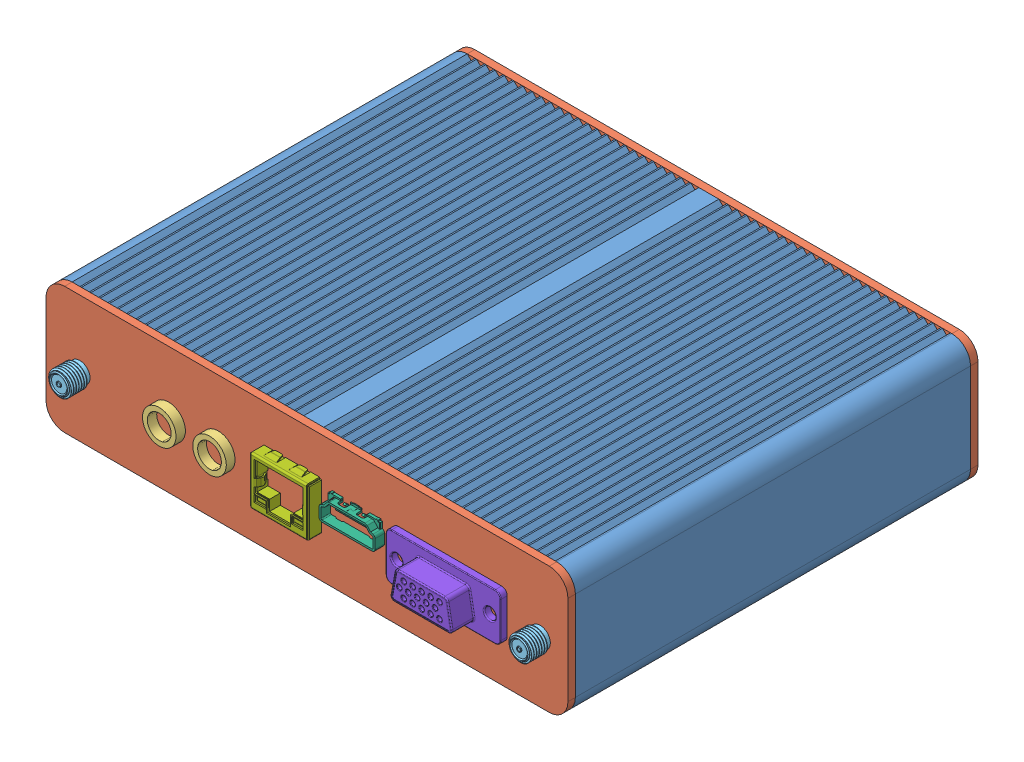
SolidWorks assembly mini computer all, configuration Default. Lengths in mm.
Overall size (140 34 122.68).
23 component instances, 13 part files, 6 mates.
Components (placement in the parent):
- mini computer enclosure body-1: mini computer enclosure body [Default] at (56.7491 81.2226 46.5464) size (140 34 106)
- mini computer back panel-1: mini computer back panel [Default] at (-0.7408 3.8203 51.7955) size (140 34 41.82)
  - mini computer enclosure sides-1: mini computer enclosure sides [Default] at (57.49 77.4023 100.7509) size (140 34 2)
  - 6.35mm jack-1: 6.35mm jack [Default] at (20.382 76.9675 85.7703) size (19 18 36.5)
    - 6.35mm jack-1: 6.35mm jack [Default] at origin size (18 18 36.5)
    - Gnd Plate_6.35mm jack-1: Gnd Plate_6.35mm jack [Default] at (0 0 10) size (17 18 20)
  - 6.35mm jack-2: 6.35mm jack [Default] at (33.7137 76.9223 85.6106) size (19 18 36.5)
    - 6.35mm jack-1: 6.35mm jack [Default] at origin size (18 18 36.5)
    - Gnd Plate_6.35mm jack-1: Gnd Plate_6.35mm jack [Default] at (0 0 10) size (17 18 20)
  - Conector SMA flange 4 furos-1: Conector SMA flange 4 furos [Valor predeterminado] at (-3.4215 76.4747 99.0509) x (1 0 0) z (0 -1 0) size (12.7 27.4 12.7)
  - Conector SMA flange 4 furos-2: Conector SMA flange 4 furos [Valor predeterminado] at (120.0439 76.6956 99.0509) x (1 0 0) z (0 -1 0) size (12.7 27.4 12.7)
  - hdmi female-2: hdmi female [Default] at (70.798 82.8969 105.3066) x (-1 0 0) z (0 0 1) size (15.14 8.38 12.15)
  - RJ45_10P_TJ3009-1: RJ45_10P_TJ3009 [Default] at (53.5571 84.0699 95.5036) x (-1 0 0) z (0 0 1) size (16 15.87 21.5)
  - VGA PORT-1: VGA PORT [По умолчанию] at (95.8113 77.1031 104.5295) x (1 0 0) z (0 0 -1) size (30.8 16.47 22.2)
- mini computer front panel-1: mini computer front panel [Default] at (110.1468 19.0094 232.1895) x (-1 0 0) z (0 0 -1) size (140 34 29)
  - mini computer enclosure sides-1: mini computer enclosure sides [Default] at (53.3977 62.2132 185.6431) size (140 34 2)
  - usb_a-usb_a-lp-c-1: usb_a-usb_a-lp-c [Default] at (55.3305 69.3871 188.406) x (-1 0 0) z (0 0 1) size (12.61 5.8 19.93)
  - usb3x2-1: usb3x2 [Default] at (78.6824 71.2528 188.5685) x (0 -1 0) z (1 0 0) size (19.41 17.47 15.68)
  - usb3x2-2: usb3x2 [Default] at (96.7049 71.3003 188.9318) x (0 -1 0) z (1 0 0) size (19.41 17.47 15.68)
  - Jack 12V DC-1: Jack 12V DC [Default] at (20.8994 57.6127 190.0972) size (9.8 15.1 14.2)
  - Push Button-1: Push Button [Default] at (67.9467 102.816 186.8199) x (1 0 0) z (0 -1 0) size (14.35 29 14.35)
    - Body-1: Body [Default] at (-63.575 0.8231 40.4617) size (14.35 26 14.35)
    - Button-1: Button [Default] at (-63.575 -0.1769 40.4617) x (0.950463 0 0.310838) z (-0.310838 0 0.950463) size (9 6 9)
Mates (geometry in assembly coordinates):
- Coincident2: coincident anti-aligned: plane of mini computer enclosure body-1 through (121.7491 93.2226 152.5464) normal (0 0 1); plane of mini computer back panel-1/mini computer enclosure sides-1 through (121.7491 93.2226 152.5464) normal (0 0 -1)
- Coincident3: coincident aligned: plane of mini computer enclosure body-1 through (-8.2509 64.2226 152.5464) normal (0 -1 0); plane of mini computer back panel-1/mini computer enclosure sides-1 through (-8.2509 64.2226 154.5464) normal (0 -1 0)
- Coincident4: coincident aligned: plane of mini computer enclosure body-1 through (-13.2509 93.2226 152.5464) normal (-1 0 0); plane of mini computer back panel-1/mini computer enclosure sides-1 through (-13.2509 93.2226 154.5464) normal (-1 0 0)
- Coincident5: coincident anti-aligned: plane of mini computer enclosure body-1 through (121.7491 93.2226 46.5464) normal (0 0 -1); plane of mini computer front panel-1/mini computer enclosure sides-1 through (-8.2509 93.2226 46.5464) normal (0 0 1)
- Coincident6: coincident aligned: plane of mini computer enclosure body-1 through (126.7491 93.2226 152.5464) normal (1 0 0); plane of mini computer front panel-1/mini computer enclosure sides-1 through (126.7491 93.2226 44.5464) normal (1 0 0)
- Coincident7: coincident aligned: plane of mini computer enclosure body-1 through (-8.2509 64.2226 152.5464) normal (0 -1 0); plane of mini computer front panel-1/mini computer enclosure sides-1 through (121.7491 64.2226 44.5464) normal (0 -1 0)
